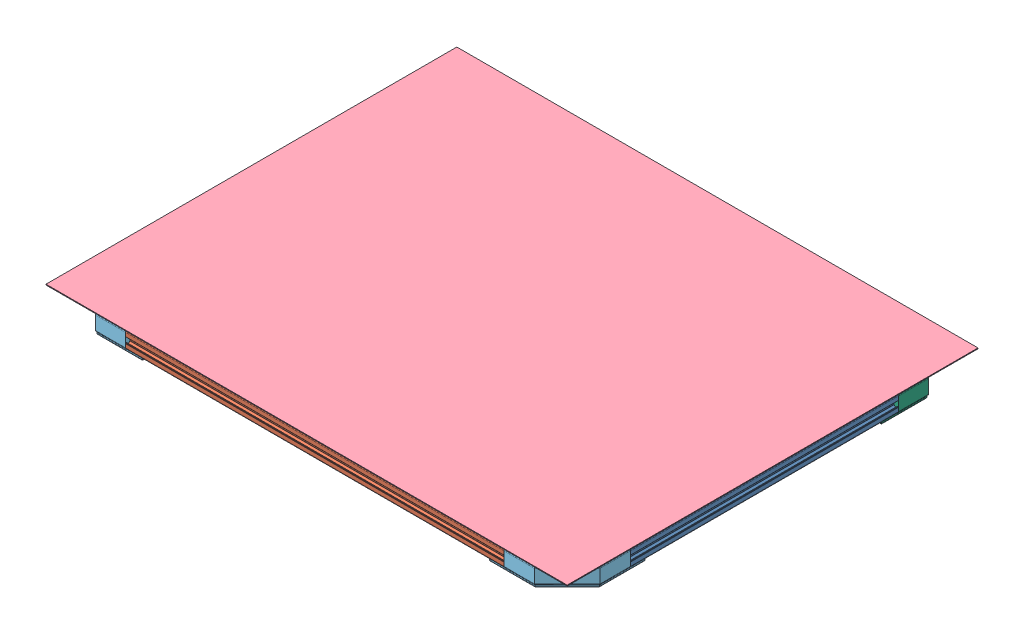
SolidWorks assembly Door, configuration Default. Lengths in mm.
Overall size (661 25 521).
9 component instances, 7 part files, 24 mates.
Components (placement in the parent):
- Profile 20x20-340mm-1: Profile 20x20-340mm [Default] at (93.8042 206.0738 77.7111) size (20 20 340)
- Profile 20x20-480mm-1: Profile 20x20-480mm [Default] at (652.3042 206.0738 479.2111) x (0 0 1) z (-1 0 0) size (20 20 480)
- Profile 20x20-340mm-2: Profile 20x20-340mm [Default] at (713.8042 206.0738 77.7111) size (20 20 340)
- Profile 20x20 LR-480mm-1: Profile 20x20 LR-480mm [Default] at (172.3042 226.0738 -0.7889) x (0 0 1) z (1 0 0) size (20 20 480)
- 661x521x1 Policarbonato-1: 661x521x1 Policarbonato [Default] at (401.8042 226.0738 237.2111) x (0 0 1) z (0 1 0) size (521 661 1)
- DoorBarCoupler-3: DoorBarCoupler [Default] at (732.3042 226.0738 497.7111) x (0 0 -1) z (-1 0 0) size (100 24 100)
- DoorBarCoupler-4: DoorBarCoupler [Default] at (92.3042 226.0738 497.7111) x (1 0 0) z (0 0 -1) size (100 24 100)
- DoorBarCouplerR1-2: DoorBarCouplerR1 [Default] at (732.3042 226.0738 -2.2889) x (-1 0 0) z (0 0 1) size (100 24 100)
- MirrorDoorBarCouplerR1-2: MirrorDoorBarCouplerR1 [Default] at (92.3042 226.0738 -2.2889) x (1 0 0) z (0 0 -1) size (100 24 100)
Mates (geometry in assembly coordinates):
- Coincident24: coincident aligned: plane of Profile 20x20-480mm-1 through (652.3042 224.5738 497.7111) normal (0 0 1); plane of 661x521x1 Policarbonato-1 through (71.3042 227.0738 497.7111) normal (0 0 1)
- Coincident25: coincident aligned: plane of Profile 20x20-340mm-2 through (732.3042 224.5738 77.7111) normal (1 0 0); plane of 661x521x1 Policarbonato-1 through (732.3042 227.0738 -23.2889) normal (1 0 0)
- Coincident26: coincident anti-aligned: plane of Profile 20x20-340mm-2 through (718.4542 206.0738 77.7111) normal (0 -1 0); plane of DoorBarCoupler-3 through (732.3042 206.0738 497.7111) normal (0 1 0)
- Coincident27: coincident anti-aligned: plane of Profile 20x20-340mm-2 through (722.3042 216.0738 417.7111) normal (0 0 1); plane of DoorBarCoupler-3 through (732.3042 206.0738 417.7111) normal (0 0 -1)
- Coincident28: coincident anti-aligned: plane of Profile 20x20-340mm-2 through (712.3042 219.9238 77.7111) normal (-1 0 0); plane of DoorBarCoupler-3 through (712.3042 226.0738 497.7111) normal (1 0 0)
- Coincident29: coincident anti-aligned: plane of Profile 20x20-480mm-1 through (652.3042 219.9238 477.7111) normal (0 0 -1); plane of DoorBarCoupler-3 through (732.3042 226.0738 477.7111) normal (0 0 1)
- Coincident30: coincident anti-aligned: plane of Profile 20x20-480mm-1 through (652.3042 206.0738 496.2111) normal (0 -1 0); plane of DoorBarCoupler-3 through (732.3042 206.0738 497.7111) normal (0 1 0)
- Coincident31: coincident anti-aligned: plane of Profile 20x20-480mm-1 through (652.3042 216.0738 487.7111) normal (1 0 0); plane of DoorBarCoupler-3 through (652.3042 206.0738 497.7111) normal (-1 0 0)
- Coincident32: coincident anti-aligned: plane of 661x521x1 Policarbonato-1 through (401.8042 226.0738 237.2111) normal (0 -1 0); plane of DoorBarCoupler-3 through (732.3042 226.0738 497.7111) normal (0 1 0)
- Coincident33: coincident anti-aligned: plane of Profile 20x20-480mm-1 through (652.3042 206.0738 483.8611) normal (0 -1 0); plane of DoorBarCoupler-4 through (92.3042 206.0738 497.7111) normal (0 1 0)
- Coincident34: coincident anti-aligned: plane of Profile 20x20-480mm-1 through (652.3042 207.5738 477.7111) normal (0 0 -1); plane of DoorBarCoupler-4 through (92.3042 226.0738 477.7111) normal (0 0 1)
- Coincident35: coincident anti-aligned: plane of Profile 20x20-480mm-1 through (172.3042 216.0738 487.7111) normal (-1 0 0); plane of DoorBarCoupler-4 through (172.3042 206.0738 497.7111) normal (1 0 0)
- Coincident36: coincident anti-aligned: plane of Profile 20x20-340mm-1 through (102.3042 216.0738 417.7111) normal (0 0 1); plane of DoorBarCoupler-4 through (92.3042 206.0738 417.7111) normal (0 0 -1)
- Coincident37: coincident anti-aligned: plane of Profile 20x20-340mm-1 through (112.3042 212.2238 77.7111) normal (1 0 0); plane of DoorBarCoupler-4 through (112.3042 226.0738 497.7111) normal (-1 0 0)
- Coincident38: coincident anti-aligned: plane of Profile 20x20-340mm-1 through (98.4542 206.0738 77.7111) normal (0 -1 0); plane of DoorBarCoupler-4 through (92.3042 206.0738 497.7111) normal (0 1 0)
- Coincident39: coincident anti-aligned: plane of Profile 20x20-340mm-2 through (718.4542 206.0738 77.7111) normal (0 -1 0); plane of DoorBarCouplerR1-2 through (732.3042 206.0738 -2.2889) normal (0 1 0)
- Coincident40: coincident anti-aligned: plane of Profile 20x20-340mm-2 through (712.3042 207.5738 77.7111) normal (-1 0 0); plane of DoorBarCouplerR1-2 through (712.3042 226.0738 -2.2889) normal (1 0 0)
- Coincident41: coincident anti-aligned: plane of Profile 20x20 LR-480mm-1 through (172.3042 207.5738 17.7111) normal (0 0 1); plane of DoorBarCouplerR1-2 through (732.3042 226.0738 17.7111) normal (0 0 -1)
- Coincident42: coincident anti-aligned: plane of Profile 20x20-340mm-2 through (722.3042 216.0738 77.7111) normal (0 0 -1); plane of DoorBarCouplerR1-2 through (732.3042 206.0738 77.7111) normal (0 0 1)
- Coincident43: coincident anti-aligned: plane of Profile 20x20 LR-480mm-1 through (172.3042 226.0738 4.0111) normal (0 1 0); plane of 661x521x1 Policarbonato-1 through (401.8042 226.0738 237.2111) normal (0 -1 0)
- Coincident44: coincident anti-aligned: plane of Profile 20x20 LR-480mm-1 through (652.3042 217.8759 9.5132) normal (1 0 0); plane of DoorBarCouplerR1-2 through (652.3042 206.0738 -2.2889) normal (-1 0 0)
- Coincident45: coincident anti-aligned: plane of Profile 20x20-340mm-1 through (98.4542 206.0738 77.7111) normal (0 -1 0); plane of MirrorDoorBarCouplerR1-2 through (92.3042 206.0738 -2.2889) normal (0 1 0)
- Coincident46: coincident anti-aligned: plane of Profile 20x20-340mm-1 through (112.3042 212.2238 77.7111) normal (1 0 0); plane of MirrorDoorBarCouplerR1-2 through (112.3042 226.0738 -2.2889) normal (-1 0 0)
- Coincident47: coincident anti-aligned: plane of Profile 20x20-340mm-1 through (102.3042 216.0738 77.7111) normal (0 0 -1); plane of MirrorDoorBarCouplerR1-2 through (92.3042 206.0738 77.7111) normal (0 0 1)
